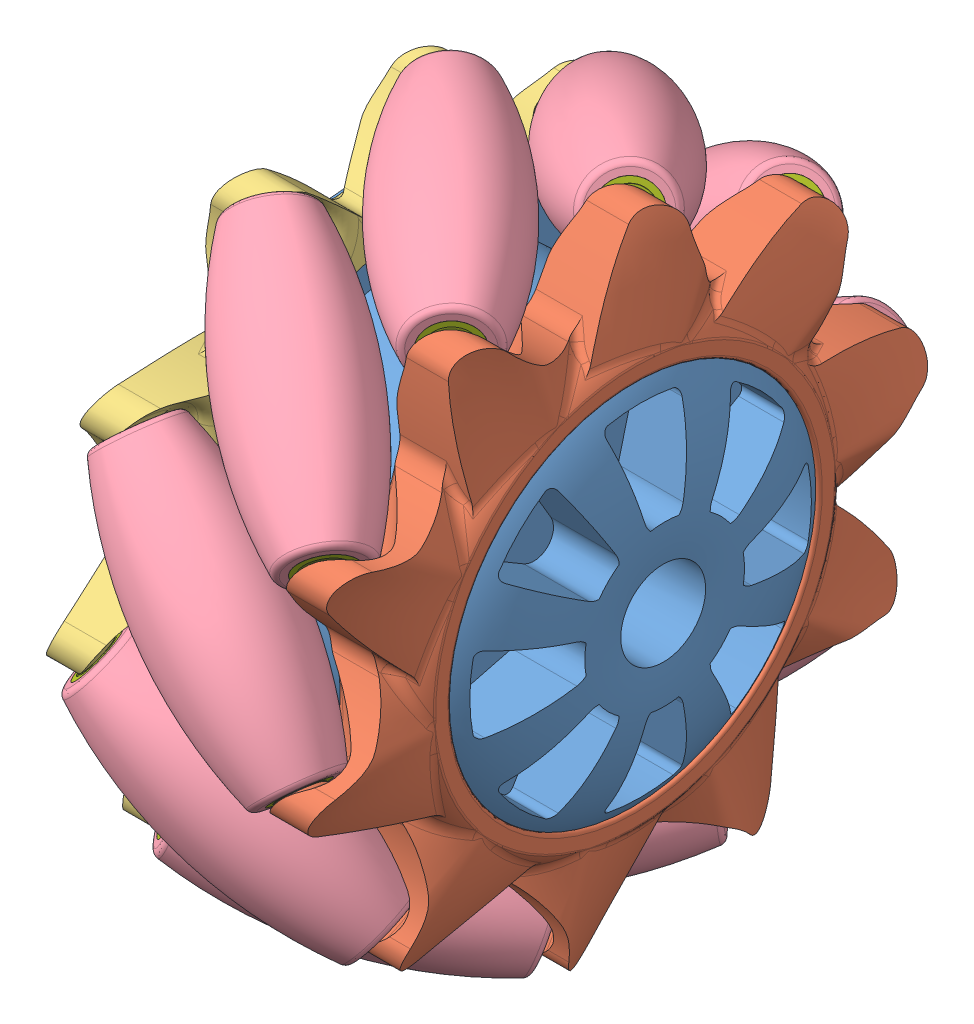
SolidWorks assembly Mecanum Wheel Assembly, configuration Default. Lengths in mm.
Overall size (34.3 66.01 67.86).
63 component instances, 7 part files, 24 mates.
Components (placement in the parent):
- Cap-1: Cap [Default] at (35.9616 -15.1476 50.8168) size (34.3 39 39)
- Front Cap-1: Front Cap [Default] at (12.1367 -15.1477 50.8171) x (0 -0.983883 0.178816) z (1 0 0) size (56.93 55.17 8.38)
- Rear Cap-1: Rear Cap [Default] at (25.7891 -15.1474 50.817) x (0 0.983883 -0.178816) z (-1 0 0) size (56.93 55.17 7.96)
- Roller Assembly-1: Roller Assembly [Default] at (19.0729 9.6766 54.1728) x (0.700732 -0.038886 -0.712364) z (0.707107 -0.094733 0.700732) size (11.4 11.4 29.4)
  - Roller-1: Roller [Default] at origin size (11.4 11.4 25.8)
  - Shaft-1: Shaft [Default] x (0.830924 -0.556385 0) z (-0.556385 -0.830924 0) size (1.8 29.4 1.8)
  - Roller Suport-1: Roller Suport [Default] at origin size (5.4 5.4 24.84)
  - Bearing-1: Bearing [Default] at (0 0 -13.4018) x (0 0 1) z (-1 0 0) size (1.9 4.86 4.86)
  - Bearing-2: Bearing [Default] at (0 0 13.4018) x (0 0 -1) z (0.923728 0.383049 0) size (1.9 4.86 4.86)
- Roller Assembly-2: Roller Assembly [Default] at (19.0729 2.963 68.1232) x (0.511222 -0.146296 -0.846906) z (0.707107 -0.488521 0.511222) size (11.4 11.4 29.4)
  - Roller-1: Roller [Default] at origin size (11.4 11.4 25.8)
  - Shaft-1: Shaft [Default] x (0.830924 -0.556385 0) z (-0.556385 -0.830924 0) size (1.8 29.4 1.8)
  - Roller Suport-1: Roller Suport [Default] at origin size (5.4 5.4 24.84)
  - Bearing-1: Bearing [Default] at (0 0 -13.4018) x (0 0 1) z (-1 0 0) size (1.9 4.86 4.86)
  - Bearing-2: Bearing [Default] at (0 0 13.4018) x (0 0 -1) z (0.923728 0.383049 0) size (1.9 4.86 4.86)
- Roller Assembly-3: Roller Assembly [Default] at (19.0729 -10.6683 75.4631) x (0.126442 -0.05153 -0.990635) z (0.707107 -0.69571 0.126442) size (11.4 11.4 29.4)
  - Roller-1: Roller [Default] at origin size (11.4 11.4 25.8)
  - Shaft-1: Shaft [Default] x (0.830924 -0.556385 0) z (-0.556385 -0.830924 0) size (1.8 29.4 1.8)
  - Roller Suport-1: Roller Suport [Default] at origin size (5.4 5.4 24.84)
  - Bearing-1: Bearing [Default] at (0 0 -13.4018) x (0 0 1) z (-1 0 0) size (1.9 4.86 4.86)
  - Bearing-2: Bearing [Default] at (0 0 13.4018) x (0 0 -1) z (0.923728 0.383049 0) size (1.9 4.86 4.86)
- Roller Assembly-4: Roller Assembly [Default] at (19.0729 -26.0105 73.389) x (-0.306634 0.114448 -0.944922) z (0.707107 -0.637162 -0.306634) size (11.4 11.4 29.4)
  - Roller-1: Roller [Default] at origin size (11.4 11.4 25.8)
  - Shaft-1: Shaft [Default] x (0.830924 -0.556385 0) z (-0.556385 -0.830924 0) size (1.8 29.4 1.8)
  - Roller Suport-1: Roller Suport [Default] at origin size (5.4 5.4 24.84)
  - Bearing-1: Bearing [Default] at (0 0 -13.4018) x (0 0 1) z (-1 0 0) size (1.9 4.86 4.86)
  - Bearing-2: Bearing [Default] at (0 0 13.4018) x (0 0 -1) z (0.923728 0.383049 0) size (1.9 4.86 4.86)
- Roller Assembly-5: Roller Assembly [Default] at (19.0729 -37.2034 62.6931) x (-0.622587 0.122263 -0.772941) z (0.707107 -0.33524 -0.622587) size (11.4 11.4 29.4)
  - Roller-1: Roller [Default] at origin size (11.4 11.4 25.8)
  - Shaft-1: Shaft [Default] x (0.830924 -0.556385 0) z (-0.556385 -0.830924 0) size (1.8 29.4 1.8)
  - Roller Suport-1: Roller Suport [Default] at origin size (5.4 5.4 24.84)
  - Bearing-1: Bearing [Default] at (0 0 -13.4018) x (0 0 1) z (-1 0 0) size (1.9 4.86 4.86)
  - Bearing-2: Bearing [Default] at (0 0 13.4018) x (0 0 -1) z (0.923728 0.383049 0) size (1.9 4.86 4.86)
- Roller Assembly-6: Roller Assembly [Default] at (19.0729 -39.9718 47.4608) x (-0.700732 -0.038886 -0.712364) z (0.707107 0.094733 -0.700732) size (11.4 11.4 29.4)
  - Roller-1: Roller [Default] at origin size (11.4 11.4 25.8)
  - Shaft-1: Shaft [Default] x (0.830924 -0.556385 0) z (-0.556385 -0.830924 0) size (1.8 29.4 1.8)
  - Roller Suport-1: Roller Suport [Default] at origin size (5.4 5.4 24.84)
  - Bearing-1: Bearing [Default] at (0 0 -13.4018) x (0 0 1) z (-1 0 0) size (1.9 4.86 4.86)
  - Bearing-2: Bearing [Default] at (0 0 13.4018) x (0 0 -1) z (0.923728 0.383049 0) size (1.9 4.86 4.86)
- Roller Assembly-7: Roller Assembly [Default] at (19.0729 -33.2582 33.5105) x (-0.519533 -0.131506 -0.84427) z (0.707107 0.488521 -0.511222) size (11.4 11.4 29.4)
  - Roller-1: Roller [Default] at origin size (11.4 11.4 25.8)
  - Shaft-1: Shaft [Default] x (0.830924 -0.556385 0) z (-0.556385 -0.830924 0) size (1.8 29.4 1.8)
  - Roller Suport-1: Roller Suport [Default] at origin size (5.4 5.4 24.84)
  - Bearing-1: Bearing [Default] at (0 0 -13.4018) x (0 0 1) z (-1 0 0) size (1.9 4.86 4.86)
  - Bearing-2: Bearing [Default] at (0 0 13.4018) x (0 0 -1) z (0.923728 0.383049 0) size (1.9 4.86 4.86)
- Roller Assembly-8: Roller Assembly [Default] at (19.0729 -19.6269 26.1706) x (-0.126442 -0.05153 -0.990635) z (0.707107 0.69571 -0.126442) size (11.4 11.4 29.4)
  - Roller-1: Roller [Default] at origin size (11.4 11.4 25.8)
  - Shaft-1: Shaft [Default] x (0.830924 -0.556385 0) z (-0.556385 -0.830924 0) size (1.8 29.4 1.8)
  - Roller Suport-1: Roller Suport [Default] at origin size (5.4 5.4 24.84)
  - Bearing-1: Bearing [Default] at (0 0 -13.4018) x (0 0 1) z (-1 0 0) size (1.9 4.86 4.86)
  - Bearing-2: Bearing [Default] at (0 0 13.4018) x (0 0 -1) z (0.923728 0.383049 0) size (1.9 4.86 4.86)
- Roller Assembly-9: Roller Assembly [Default] at (19.0729 -4.2848 28.2447) x (0.616675 -0.343487 -0.708328) z (0.707107 0.637162 0.306634) size (11.4 11.4 29.4)
  - Roller-1: Roller [Default] at origin size (11.4 11.4 25.8)
  - Shaft-1: Shaft [Default] x (0.830924 -0.556385 0) z (-0.556385 -0.830924 0) size (1.8 29.4 1.8)
  - Roller Suport-1: Roller Suport [Default] at origin size (5.4 5.4 24.84)
  - Bearing-1: Bearing [Default] at (0 0 -13.4018) x (0 0 1) z (-1 0 0) size (1.9 4.86 4.86)
  - Bearing-2: Bearing [Default] at (0 0 13.4018) x (0 0 -1) z (0.923728 0.383049 0) size (1.9 4.86 4.86)
- Roller Assembly-10: Roller Assembly [Default] at (19.0729 6.9082 38.9406) x (0.622587 0.122263 -0.772941) z (0.707107 0.33524 0.622587) size (11.4 11.4 29.4)
  - Roller-1: Roller [Default] at origin size (11.4 11.4 25.8)
  - Shaft-1: Shaft [Default] x (0.830924 -0.556385 0) z (-0.556385 -0.830924 0) size (1.8 29.4 1.8)
  - Roller Suport-1: Roller Suport [Default] at origin size (5.4 5.4 24.84)
  - Bearing-1: Bearing [Default] at (0 0 -13.4018) x (0 0 1) z (-1 0 0) size (1.9 4.86 4.86)
  - Bearing-2: Bearing [Default] at (0 0 13.4018) x (0 0 -1) z (0.923728 0.383049 0) size (1.9 4.86 4.86)
Mates (geometry in assembly coordinates):
- Concentric10: concentric anti-aligned: cylinder of DDMW RightFrontCap-1 through (-7.2997 -51.4783 52.5772) axis (0.707107 0.488521 -0.511222) radius 0.9; cylinder of DDMW RightRearCap-1 through (45.4454 -15.0381 14.4437) axis (-0.707107 -0.488521 0.511222) radius 0.9
- Concentric37: concentric anti-aligned: cylinder of Cap-1 through (34.0729 -15.1476 50.8168) axis (-1 0 0) radius 16.8; cylinder of DDMW RightFrontCap-1 through (5.5723 -15.1476 50.8168) axis (1 0 0) radius 16.8
- Coincident17: coincident anti-aligned: circle of Cap-1; circle of DDMW RightFrontCap-1
- Concentric38: concentric anti-aligned: cylinder of Cap-1 through (12.4729 -15.1476 50.8168) axis (-1 0 0) radius 19.5; cylinder of DDMW RightRearCap-1 through (5.5729 -15.1476 50.8168) axis (1 0 0) radius 19.5
- Concentric56: concentric anti-aligned: cylinder of DDMW RightFrontCap-1 through (-7.2997 -51.4783 52.5772) axis (0.707107 0.488521 -0.511222) radius 0.9; cylinder of Roller Assembly-7/Shaft-1 through (29.4673 -26.0769 25.9955) axis (-0.707107 -0.488521 0.511222) radius 0.9
- Coincident26: coincident anti-aligned: plane of DDMW RightRearCap-1 through (9.9512 -39.5601 40.1052) normal (0.707107 0.488521 -0.511222); plane of Roller Assembly-7/W 638_3 R-2RS1-1 through (8.7952 -37.4813 40.4928) normal (-0.707107 -0.488521 0.511222)
- Concentric57: concentric anti-aligned: cylinder of DDMW RightFrontCap-1 through (-2.6812 -41.0304 30.0605) axis (0.707107 0.69571 -0.126442) radius 0.9; cylinder of Roller Assembly-8/Shaft-1 through (29.4673 -9.4 24.3119) axis (-0.707107 -0.69571 0.126442) radius 0.9
- Concentric58: concentric anti-aligned: cylinder of DDMW RightFrontCap-1 through (-7.2997 -28.0486 16.8083) axis (0.707107 0.637162 0.306634) radius 0.9; cylinder of Roller Assembly-9/Shaft-1 through (29.4673 5.0815 32.7522) axis (-0.707107 -0.637162 -0.306634) radius 0.9
- Concentric59: concentric anti-aligned: cylinder of DDMW RightFrontCap-1 through (-5.1931 -4.5963 17.5752) axis (0.707107 0.33524 0.622587) radius 0.9; cylinder of Roller Assembly-10/Shaft-1 through (29.4673 11.8362 48.0927) axis (-0.707107 -0.33524 -0.622587) radius 0.9
- Concentric60: concentric anti-aligned: cylinder of DDMW RightFrontCap-1 through (-5.1931 12.9275 30.1257) axis (0.707107 -0.094733 0.700732) radius 0.9; cylinder of Roller Assembly-1/Shaft-1 through (29.4673 8.284 64.4736) axis (-0.707107 0.094733 -0.700732) radius 0.9
- Concentric61: concentric anti-aligned: cylinder of DDMW RightFrontCap-1 through (-7.2997 21.183 49.0564) axis (0.707107 -0.488521 0.511222) radius 0.9; cylinder of Roller Assembly-2/Shaft-1 through (29.4673 -4.2183 75.6382) axis (-0.707107 0.488521 -0.511222) radius 0.9
- Concentric62: concentric anti-aligned: cylinder of DDMW RightFrontCap-1 through (-1.9113 9.9777 71.7108) axis (0.707107 -0.69571 0.126442) radius 0.9; cylinder of Roller Assembly-3/Shaft-1 through (29.4673 -20.8952 77.3218) axis (-0.707107 0.69571 -0.126442) radius 0.9
- Concentric63: concentric anti-aligned: cylinder of DDMW RightFrontCap-1 through (-7.2997 -2.2466 84.8253) axis (0.707107 -0.637162 -0.306634) radius 0.9; cylinder of Roller Assembly-4/Shaft-1 through (29.4673 -35.3767 68.8814) axis (-0.707107 0.637162 0.306634) radius 0.9
- Concentric64: concentric anti-aligned: cylinder of DDMW RightFrontCap-1 through (-5.1931 -25.6989 84.0585) axis (0.707107 -0.33524 -0.622587) radius 0.9; cylinder of Roller Assembly-5/Shaft-1 through (29.4673 -42.1314 53.541) axis (-0.707107 0.33524 0.622587) radius 0.9
- Concentric65: concentric anti-aligned: cylinder of DDMW RightFrontCap-1 through (-5.1931 -43.2228 71.508) axis (0.707107 0.094733 -0.700732) radius 0.9; cylinder of Roller Assembly-6/Shaft-1 through (29.4673 -38.5792 37.1601) axis (-0.707107 -0.094733 0.700732) radius 0.9
- Coincident27: coincident anti-aligned: plane of DDMW RightRearCap-1 through (9.9512 -28.6016 27.8017) normal (0.707107 0.69571 -0.126442); plane of Roller Assembly-8/W 638_3 R-2RS1-1 through (8.2745 -26.8749 27.9259) normal (-0.707107 -0.69571 0.126442)
- Coincident28: coincident aligned: plane of DDMW RightRearCap-1 through (9.9512 -12.5042 24.2891) normal (0.707107 0.637162 0.306634); circle of Roller Assembly-9/W 638_3 R-2RS1-1
- Coincident29: coincident anti-aligned: plane of DDMW RightRearCap-1 through (9.9512 2.5836 30.9093) normal (0.707107 0.33524 0.622587); plane of Roller Assembly-10/W 638_3 R-2RS1-1 through (9.1433 4.8349 30.6146) normal (-0.707107 -0.33524 -0.622587)
- Coincident30: coincident anti-aligned: plane of DDMW RightRearCap-1 through (9.9512 10.8986 45.1334) normal (0.707107 -0.094733 0.700732); plane of Roller Assembly-1/W 638_3 R-2RS1-1 through (10.1795 13.296 45.2271) normal (-0.707107 0.094733 -0.700732)
- Coincident31: coincident anti-aligned: plane of DDMW RightRearCap-1 through (9.9512 9.2649 61.5284) normal (0.707107 -0.488521 0.511222); plane of Roller Assembly-2/W 638_3 R-2RS1-1 through (11.1285 11.338 61.881) normal (-0.707107 0.488521 -0.511222)
- Coincident32: coincident anti-aligned: plane of DDMW RightRearCap-1 through (9.9512 -1.6936 73.832) normal (0.707107 -0.69571 0.126442); plane of Roller Assembly-3/W 638_3 R-2RS1-1 through (11.6278 0.0331 73.9562) normal (-0.707107 0.69571 -0.126442)
- Coincident33: coincident anti-aligned: plane of DDMW RightRearCap-1 through (9.9512 -17.7911 77.3446) normal (0.707107 -0.637162 -0.306634); plane of Roller Assembly-4/W 638_3 R-2RS1-1 through (11.4867 -15.9542 77.0687) normal (-0.707107 0.637162 0.306634)
- Coincident34: coincident anti-aligned: plane of DDMW RightRearCap-1 through (9.9512 -32.8788 70.7244) normal (0.707107 -0.33524 -0.622587); plane of Roller Assembly-5/W 638_3 R-2RS1-1 through (10.7591 -30.6275 70.4298) normal (-0.707107 0.33524 0.622587)
- Coincident35: coincident anti-aligned: plane of DDMW RightRearCap-1 through (9.9512 -41.1938 56.5003) normal (0.707107 0.094733 -0.700732); plane of Roller Assembly-6/W 638_3 R-2RS1-1 through (9.7229 -38.7965 56.594) normal (-0.707107 -0.094733 0.700732)
